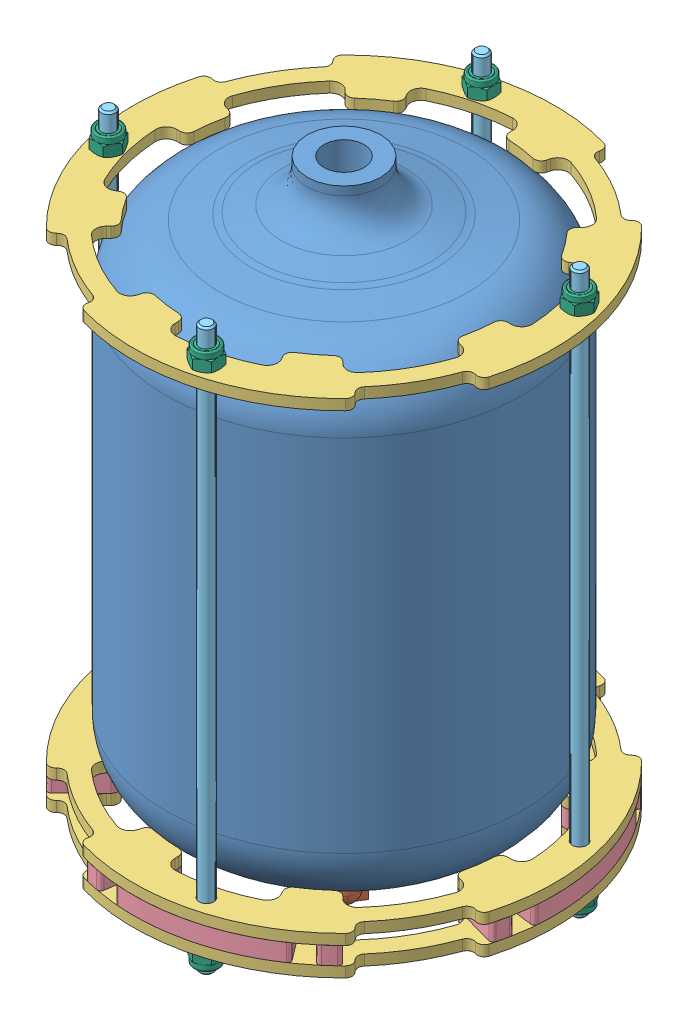
SolidWorks assembly P11_Alu_Fuel_Tank, configuration Standard. Lengths in mm.
Overall size (159.1 188.94 159.1).
21 component instances, 6 part files, 21 mates.
Components (placement in the parent):
- P11_Alu_Fuel_Tank-1: P11_Alu_Fuel_Tank [Standard] at (0 170 0) size (101.6 170 101.6)
- P12_6mm_G-1-4_Elbow-1: P12_6mm_G-1-4_Elbow [Default] at (0 10 0) x (-0.837169 0 -0.546944) z (-0.546944 0 0.837169) size (30.81 27.94 17.53)
- P14_P15_Fuel_Tank_Bracket-1: P14_P15_Fuel_Tank_Bracket [Default] at (0 149.5248 0) x (0.863547 0 0.504268) z (-0.504268 0 0.863547) size (116.32 3 116.32)
- P14_P15_Fuel_Tank_Bracket-2: P14_P15_Fuel_Tank_Bracket [Default] at (0 17.4752 0) x (0.863547 0 0.504268) z (-0.504268 0 0.863547) size (116.32 3 116.32)
- P14_P15_Fuel_Tank_Bracket-3: P14_P15_Fuel_Tank_Bracket [Default] at (0 9.4752 0) x (0.863547 0 0.504268) z (-0.504268 0 0.863547) size (116.32 3 116.32)
- Sub_P15_Bracket_Spacer-1: Sub_P15_Bracket_Spacer [Default] at (0 12.4752 0) x (0.863547 0 0.504268) z (-0.504268 0 0.863547) size (45.64 5 45.64)
- Sub_P15_Bracket_Spacer-2: Sub_P15_Bracket_Spacer [Default] at (0 12.4752 0) x (0.504268 0 -0.863547) z (0.863547 0 0.504268) size (45.64 5 45.64)
- Sub_P15_Bracket_Spacer-3: Sub_P15_Bracket_Spacer [Default] at (0 12.4752 0) x (-0.863547 0 -0.504268) z (0.504268 0 -0.863547) size (45.64 5 45.64)
- Sub_P15_Bracket_Spacer-4: Sub_P15_Bracket_Spacer [Default] at (0 12.4752 0) x (-0.504268 0 0.863547) z (-0.863547 0 -0.504268) size (45.64 5 45.64)
- Fastener_ThreadedRod_M4_160-1: Fastener_ThreadedRod_M4_160 [Default] at (-13.9727 2.5248 -53.1955) size (4 160 4)
- Fastener_ThreadedRod_M4_160-2: Fastener_ThreadedRod_M4_160 [Default] at (-53.1955 2.5248 13.9727) x (0 0 -1) z (1 0 0) size (4 160 4)
- Fastener_ThreadedRod_M4_160-3: Fastener_ThreadedRod_M4_160 [Default] at (13.9727 2.5248 53.1955) x (-1 0 0) z (0 0 -1) size (4 160 4)
- Fastener_ThreadedRod_M4_160-4: Fastener_ThreadedRod_M4_160 [Default] at (53.1955 2.5248 -13.9727) x (0 0 1) z (-1 0 0) size (4 160 4)
- Fastener_Locknut_M4-29: Fastener_Locknut_M4 [M4 NYLOC] at (53.1955 152.5248 -13.9727) size (8.08 5 7)
- Fastener_Locknut_M4-2: Fastener_Locknut_M4 [M4 NYLOC] at (53.1955 9.4752 -13.9727) x (1 0 0) z (0 0 -1) size (8.08 5 7)
- Fastener_Locknut_M4-30: Fastener_Locknut_M4 [M4 NYLOC] at (-13.9727 152.5248 -53.1955) x (0 0 -1) z (1 0 0) size (8.08 5 7)
- Fastener_Locknut_M4-31: Fastener_Locknut_M4 [M4 NYLOC] at (-53.1955 152.5248 13.9727) x (-1 0 0) z (0 0 -1) size (8.08 5 7)
- Fastener_Locknut_M4-32: Fastener_Locknut_M4 [M4 NYLOC] at (13.9727 152.5248 53.1955) x (0 0 1) z (-1 0 0) size (8.08 5 7)
- Fastener_Locknut_M4-26: Fastener_Locknut_M4 [M4 NYLOC] at (-13.9727 9.4752 -53.1955) x (0 0 -1) z (-1 0 0) size (8.08 5 7)
- Fastener_Locknut_M4-27: Fastener_Locknut_M4 [M4 NYLOC] at (-53.1955 9.4752 13.9727) x (-1 0 0) z (0 0 1) size (8.08 5 7)
- Fastener_Locknut_M4-28: Fastener_Locknut_M4 [M4 NYLOC] at (13.9727 9.4752 53.1955) x (0 0 1) z (1 0 0) size (8.08 5 7)
Mates (geometry in assembly coordinates):
- Konzentrisch1: concentric: cylinder of P11_Alu_Fuel_Tank-1 through (0 183.4642 0) axis (0 1 0) radius 50.8
- Deckungsgleich2: coincident: plane of P11_Alu_Fuel_Tank-1 through (0 0 0) normal (0 -1 0)
- Konzentrisch2: concentric anti-aligned: cylinder of P11_Alu_Fuel_Tank-1 through (0 0 0) axis (0 -1 0) radius 5.7225; cone of P12_6mm_G-1-4_Elbow-1 through (0 7.6864 0) axis (0 1 0)
- Abstand1: distance = 7 mm anti-aligned: plane of P12_6mm_G-1-4_Elbow-1 through (6.056 7 -1.2993) normal (0 1 0); plane of P11_Alu_Fuel_Tank-1 through (0 0 0) normal (0 -1 0)
- Konzentrisch3: concentric aligned: cylinder of P11_Alu_Fuel_Tank-1 through (0 183.4642 0) axis (0 1 0) radius 50.8; cylinder of P14_P15_Fuel_Tank_Bracket-1 through (0 149.5248 0) axis (0 1 0) radius 51
- Konzentrisch4: concentric aligned: cylinder of P11_Alu_Fuel_Tank-1 through (0 183.4642 0) axis (0 1 0) radius 50.8; cylinder of P14_P15_Fuel_Tank_Bracket-2 through (0 17.4752 0) axis (0 1 0) radius 51
- Konzentrisch5: concentric aligned: cylinder of P11_Alu_Fuel_Tank-1 through (0 183.4642 0) axis (0 1 0) radius 50.8; cylinder of P14_P15_Fuel_Tank_Bracket-3 through (0 9.4752 0) axis (0 1 0) radius 51
- Konzentrisch6: concentric aligned: cylinder of P14_P15_Fuel_Tank_Bracket-2 through (-13.9727 17.4752 -53.1955) axis (0 1 0) radius 2.1; cylinder of P14_P15_Fuel_Tank_Bracket-3 through (-13.9727 9.4752 -53.1955) axis (0 1 0) radius 2.1
- Konzentrisch7: concentric aligned: cylinder of P14_P15_Fuel_Tank_Bracket-1 through (-13.9727 149.5248 -53.1955) axis (0 1 0) radius 2.1; cylinder of P14_P15_Fuel_Tank_Bracket-2 through (-13.9727 17.4752 -53.1955) axis (0 1 0) radius 2.1
- Konzentrisch8: concentric aligned: cylinder of P11_Alu_Fuel_Tank-1 through (0 183.4642 0) axis (0 1 0) radius 50.8; cylinder of Sub_P15_Bracket_Spacer-1 through (0 12.4752 0) axis (0 1 0) radius 51
- Deckungsgleich4: coincident anti-aligned: plane of P14_P15_Fuel_Tank_Bracket-2 through (0 17.4752 0) normal (0 -1 0); plane of Sub_P15_Bracket_Spacer-1 through (0 17.4752 0) normal (0 1 0)
- Deckungsgleich5: coincident anti-aligned: plane of P14_P15_Fuel_Tank_Bracket-3 through (0 12.4752 0) normal (0 1 0); plane of Sub_P15_Bracket_Spacer-1 through (0 12.4752 0) normal (0 -1 0)
- Konzentrisch9: concentric aligned: cylinder of P14_P15_Fuel_Tank_Bracket-2 through (53.1955 17.4752 -13.9727) axis (0 1 0) radius 2.1; cylinder of Sub_P15_Bracket_Spacer-1 through (53.1955 12.4752 -13.9727) axis (0 1 0) radius 2.1
- Konzentrisch10: concentric anti-aligned: cylinder of P14_P15_Fuel_Tank_Bracket-1 through (-13.9727 149.5248 -53.1955) axis (0 1 0) radius 2.1; cylinder of Fastener_ThreadedRod_M4_160-1 through (-13.9727 162.5248 -53.1955) axis (0 -1 0) radius 2
- Abstand2: distance = 10 mm aligned: plane of Fastener_ThreadedRod_M4_160_-1 through (-13.9727 162.5248 -53.1955) normal (0 1 0); plane of P14_P15_Fuel_Tank_Bracket-1 through (0 152.5248 0) normal (0 1 0)
- Deckungsgleich12: coincident: torus of P11_Alu_Fuel_Tank-1; point of P14_P15_Fuel_Tank_Bracket-2
- Konzentrisch11: concentric anti-aligned: cylinder of Fastener_ThreadedRod_M4_160-4 through (53.1955 162.5248 -13.9727) axis (0 -1 0) radius 2; cylinder of Fastener_Locknut_M4-1 through (53.1955 152.5248 -13.9727) axis (0 1 0) radius 1.5706
- Deckungsgleich13: coincident anti-aligned: plane of P14_P15_Fuel_Tank_Bracket-1 through (0 152.5248 0) normal (0 1 0); plane of Fastener_Locknut_M4-1 through (57.237 152.5248 -13.9727) normal (0 -1 0)
- Konzentrisch12: concentric aligned: cylinder of Fastener_ThreadedRod_M4_160-4 through (53.1955 162.5248 -13.9727) axis (0 -1 0) radius 2; cylinder of Fastener_Locknut_M4-2 through (53.1955 9.4752 -13.9727) axis (0 -1 0) radius 1.5706
- Deckungsgleich14: coincident anti-aligned: plane of P14_P15_Fuel_Tank_Bracket-3 through (0 9.4752 0) normal (0 -1 0); plane of Fastener_Locknut_M4-2 through (57.237 9.4752 -13.9727) normal (0 1 0)
- Abstand4: distance = 17.4752 mm aligned: plane of P11_Alu_Fuel_Tank-1 through (0 170 0) normal (0 1 0); plane of P14_P15_Fuel_Tank_Bracket-1 through (0 152.5248 0) normal (0 1 0)
